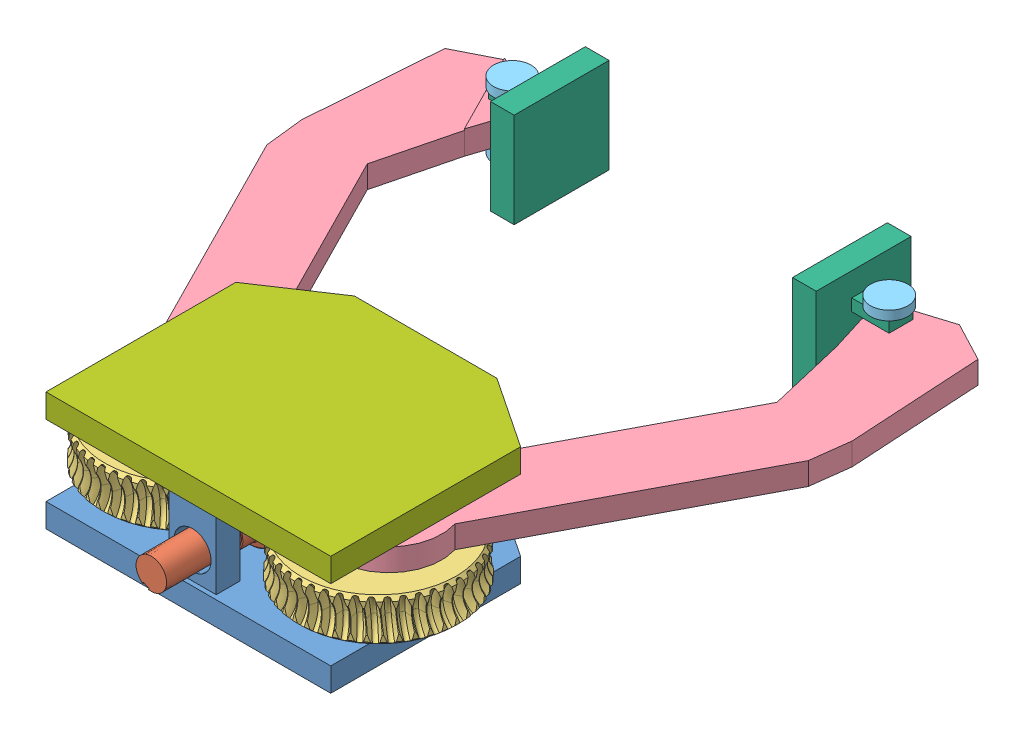
SolidWorks assembly Gripper Assembly LP, configuration Default. Lengths in mm.
Overall size (190.16 34.7 159.05).
11 component instances, 7 part files, 27 mates.
Components (placement in the parent):
- Gripper Struture-1: Gripper Struture [Default] at (21.1963 27.0165 70.9756) size (76.2 25.4 63.5)
- Screw-1: Screw [Default] at (16.6641 29.6636 35.0888) x (0 0 1) z (0.92524 -0.379382 0) size (83.73 14.51 18)
- worm gear-1: worm gear [Default] at (47.3667 40.5415 46.3338) x (0.993303 0 0.115536) z (0 -1 0) size (44.95 44.95 11.35)
- worm gear-2: worm gear [Default] at (-5.1175 40.5415 46.3337) x (0.986696 0 -0.162575) z (0 -1 0) size (44.95 44.95 11.35)
- Gripper Arm-1: Gripper Arm [Default] at (94.4548 52.2165 -21.6511) x (-0.4659 0 0.884837) z (0.884837 0 0.4659) size (134.65 6.35 47.38)
- Gripper Arm-2: Gripper Arm [Default] at (-51.1555 46.2165 -22.3676) x (0.452229 0 0.891902) z (-0.891902 0 0.452229) size (134.65 6.35 47.38)
- Gripper Pin-1: Gripper Pin [Default] at (72.5948 42.6165 -65.1655) x (-0.173272 0 -0.984874) z (0.984874 0 -0.173272) size (10 17.8 10)
- Gripper Pin-2: Gripper Pin [Default] at (-28.6285 42.6165 -65.5404) size (10 17.8 10)
- Gripper Pad-1: Gripper Pad [Default] at (65.7644 49.0165 -65.1655) x (0 0 1) z (-1 0 0) size (25.4 25.4 16.35)
- Gripper Pad-2: Gripper Pad [Default] at (-21.7981 49.0165 -65.5404) x (0 0 -1) z (1 0 0) size (25.4 25.4 16.35)
- Gripper Top-1: Gripper Top [Default] at (21.1963 52.4165 70.9756) size (76.2 6.35 63.5)
Mates (geometry in assembly coordinates):
- Concentric2: concentric: cylinder of Gripper Struture-1 through (21.124 40.5411 16.4644) axis (0 0 1) radius 5; cylinder of Screw-1 through (21.124 40.5411 80.8144) axis (0 0 1) radius 4.5
- Coincident1: coincident: plane of Gripper Struture-1 through (14.774 52.4165 22.8144) normal (0 0 -1); plane of Screw-1 through (21.124 40.5411 22.8144) normal (0 0 -1)
- Coincident3: coincident: plane of Gripper Struture-1 through (21.1963 33.3665 70.9756) normal (0 1 0); plane of ? through (43.8563 33.3665 45.1877) normal (0 -1 0)
- Coincident4: coincident: plane of Gripper Struture-1 through (21.1963 33.3665 70.9756) normal (0 1 0); plane of ? through (25.6213 33.3665 34.183) normal (0 -1 0)
- Concentric3: concentric: cylinder of Gripper Struture-1 through (47.3695 52.4165 46.3094) axis (0 -1 0) radius 5.5; cylinder of worm gear-1 through (47.3695 34.8665 46.3094) axis (0 1 0) radius 5.5
- Concentric4: concentric: cylinder of Gripper Struture-1 through (-5.1215 52.4165 46.3094) axis (0 -1 0) radius 5.5; cylinder of worm gear-2 through (-5.1215 34.8665 46.3094) axis (0 1 0) radius 5.5
- Distance1: distance = 1.5 mm: plane of Gripper Struture-1 through (21.1963 33.3665 70.9756) normal (0 1 0); plane of worm gear-1 through (47.3695 34.8665 46.3094) normal (0 -1 0)
- Distance2: distance = 1.5 mm: plane of Gripper Struture-1 through (21.1963 33.3665 70.9756) normal (0 1 0); plane of worm gear-2 through (-5.1215 34.8665 46.3094) normal (0 -1 0)
- GearMate2: gear = 10 : 500 mm: cylinder of worm gear-2 through (-5.1215 34.8665 46.3094) axis (0 1 0) radius 5.5; cylinder of Screw-1 through (21.124 40.5411 80.8144) axis (0 0 1) radius 4.1
- GearMate5: gear = 500 : 10 mm: cylinder of Screw-1 through (21.124 40.5411 80.8144) axis (0 0 1) radius 4.1; cylinder of worm gear-1 through (47.3695 34.8665 46.3094) axis (0 1 0) radius 5.5
- Concentric6: concentric: cylinder of Gripper Struture-1 through (47.3695 52.4165 46.3094) axis (0 -1 0) radius 5.5; cylinder of Gripper Arm-1 through (47.3695 52.5665 46.3094) axis (0 -1 0) radius 5.5179
- Coincident7: coincident: plane of worm gear-1 through (47.3695 46.2165 46.3094) normal (0 1 0); plane of Gripper Arm-1 through (48.3344 46.2165 44.4768) normal (0 -1 0)
- Coincident8: coincident: plane of worm gear-2 through (-5.1215 46.2165 46.3094) normal (0 1 0); plane of Gripper Arm-2 through (-6.0581 46.2165 44.4622) normal (0 -1 0)
- Concentric7: concentric: cylinder of Gripper Struture-1 through (-5.1215 52.4165 46.3094) axis (0 -1 0) radius 5.5; cylinder of Gripper Arm-2 through (-5.1215 45.8665 46.3094) axis (0 1 0) radius 5.5179
- Coincident9: coincident: plane of Gripper Arm-1 through (48.3344 52.2165 44.4768) normal (0 1 0); plane of Gripper Pad-1 through (75.7644 52.2165 -61.9655) normal (0 -1 0)
- Concentric8: concentric: cylinder of Gripper Arm-1 through (72.5948 45.8665 -65.1655) axis (0 1 0) radius 2.5; cylinder of Gripper Pad-1 through (72.5948 36.3165 -65.1655) axis (0 1 0) radius 2.4987
- Concentric10: concentric: cylinder of Gripper Pin-1 through (72.5948 55.4165 -65.1655) axis (0 -1 0) radius 2.5; cylinder of Gripper Pad-1 through (72.5948 36.3165 -65.1655) axis (0 1 0) radius 2.4987
- Coincident12: coincident: plane of Gripper Pin-1 through (72.5948 55.4165 -65.1655) normal (0 -1 0); plane of Gripper Pad-1 through (75.7644 55.4165 -61.9655) normal (0 1 0)
- Concentric11: concentric: cylinder of Gripper Arm-2 through (-28.6285 52.5665 -65.5404) axis (0 -1 0) radius 2.5; cylinder of Gripper Pad-2 through (-28.6285 36.3165 -65.5404) axis (0 1 0) radius 2.4987
- Coincident13: coincident: plane of Gripper Arm-2 through (-6.0581 52.2165 44.4622) normal (0 1 0); plane of Gripper Pad-2 through (-31.7981 52.2165 -68.7404) normal (0 -1 0)
- Coincident14: coincident: plane of Gripper Pin-2 through (-28.6285 55.4165 -65.5404) normal (0 -1 0); plane of Gripper Pad-2 through (-31.7981 55.4165 -68.7404) normal (0 1 0)
- Concentric12: concentric: cylinder of Gripper Pin-2 through (-28.6285 55.4165 -65.5404) axis (0 -1 0) radius 2.5; circle of Gripper Pad-2
- Perpendicular2: perpendicular: plane of Gripper Struture-1 through (2.1463 33.3665 7.4756) normal (0 0 -1); plane of Gripper Pad-1 through (59.4144 49.0165 -65.1655) normal (-1 0 0)
- Perpendicular3: perpendicular: plane of Gripper Struture-1 through (2.1463 33.3665 7.4756) normal (0 0 -1); plane of Gripper Pad-2 through (-15.4481 49.0165 -65.5404) normal (1 0 0)
- Coincident15: coincident: plane of Gripper Struture-1 through (2.1463 33.3665 7.4756) normal (0 0 -1); plane of Gripper Top-1 through (2.1463 58.7665 7.4756) normal (0 0 -1)
- Coincident16: coincident: plane of Gripper Struture-1 through (-16.9037 33.3665 70.9756) normal (-1 0 0); plane of Gripper Top-1 through (-16.9037 58.7665 70.9756) normal (-1 0 0)
- Coincident18: coincident: plane of Gripper Struture-1 through (21.1963 52.4165 30.3356) normal (0 1 0); plane of Gripper Top-1 through (21.1963 52.4165 70.9756) normal (0 -1 0)
